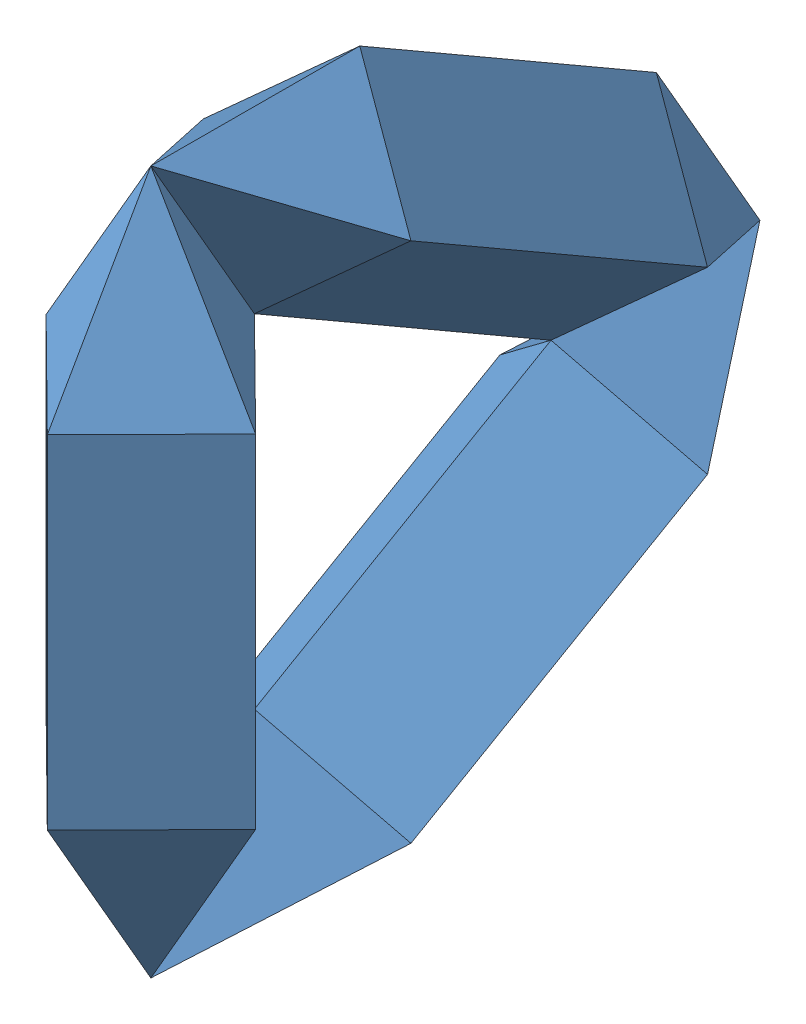
SolidWorks assembly Assemblage1, configuration Défaut. Lengths in mm.
Overall size (608.24 2580.37 2234.66).
3 component instances, 1 part files, 8 mates.
Components (placement in the parent):
- Ballon-1: Ballon [Défaut] at (0 2690.0144 1996.3959) x (0 1 0) z (-0.702937 0 0.711252) size (2053.61 430.1 430.1)
- Ballon-2: Ballon [Défaut] at (-305.9095 2689.9881 1694.0171) x (0 0.5 -0.866025) z (-0.702937 -0.615962 -0.355626) size (2053.61 430.1 430.1)
- Ballon-3: Ballon [Défaut] at (-608.2427 3454.9661 675.0369) x (0 0.5 0.866025) z (0.711252 0.608761 -0.351469) size (2053.61 430.1 430.1)
Mates (geometry in assembly coordinates):
- Angle1: planar angle = 1.308997 rad aligned: line of Ballon-1 through (0 3690.0144 1996.3959) axis (-0.711252 0 -0.702937); line of Ballon-3 through (0 3951.869 1542.8504) axis (-0.711252 -0.608761 0.351469)
- Angle2: planar angle = 1.308997 rad anti-aligned: line of Ballon-1 through (-305.9095 2690.0144 1694.0626) axis (0.711252 0 0.702937); line of Ballon-2 through (0 2428.1599 1542.8504) axis (-0.711252 0.608761 0.351469)
- Angle3: planar angle = 1.308997 rad anti-aligned: line of Ballon-3 through (0 3451.869 676.825) axis (-0.711252 -0.608761 0.351469); line of Ballon-2 through (-305.9095 3189.9881 827.9917) axis (0.711252 -0.608761 -0.351469)
- Coïncidente4: coincident: point of Ballon-1; point of Ballon-2
- Coïncidente7: coincident: point of Ballon-2; point of Ballon-3
- Coïncidente8: coincident: point of Ballon-1; point of Ballon-3
- Coïncidente9: coincident: line of Ballon-2 through (0 2928.1599 676.825) axis (0 -0.5 0.866025); plane of assembly
- Parallèle3: parallel: plane of assembly through (0 0 0) normal (0 0 1); line of Ballon-1 through (-302.3333 2690.0144 2302.3053) axis (0 1 0)
